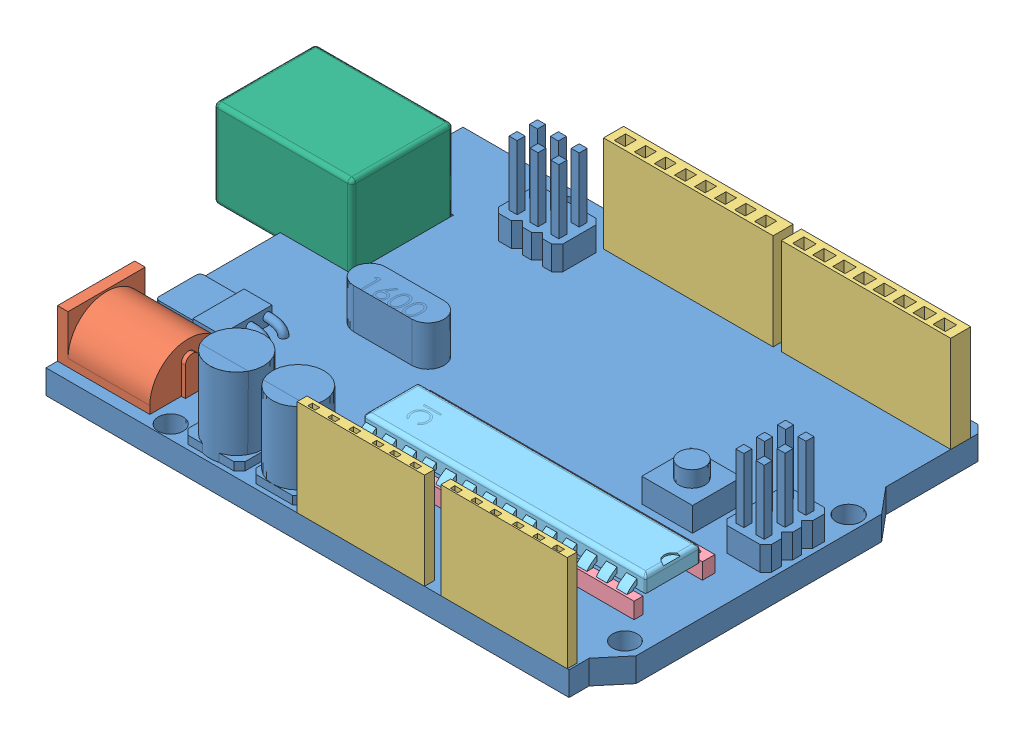
SolidWorks assembly Arduino Uno, configuration Predeterminado. Lengths in mm.
Overall size (76.16 15 51.98).
6 component instances, 6 part files, 11 mates.
Components (placement in the parent):
- Arduino Board-1: Arduino Board [Predeterminado] at (-14.2075 29.4682 76.4447) size (67.88 14 51.98)
- Jam Socket-1: Jam Socket [Predeterminado] at origin size (12.01 7 9.62)
- Pins Socket-1: Pins Socket [Predeterminado] at origin size (43.28 12 50.07)
- Socket IC-1: Socket IC [Predeterminado] at origin size (35.47 2 10.08)
- IC-1: IC [Predeterminado] at (0 34.4682 0) x (1 0 0) z (0 1 0) size (35.12 9.79 3)
- Port USB-1: Port USB [Predeterminado] at (-14.2075 31.4682 76.4447) x (1 0 0) z (0 1 0) size (17.2 12.69 11)
Mates (geometry in assembly coordinates):
- Coincidente1: coincident anti-aligned: plane of Arduino Board-1 through (-14.2075 32.4682 76.4447) normal (0 1 0); plane of Pins Socket-1 through (0 32.4682 0) normal (0 -1 0)
- Coincidente3: coincident aligned: plane of Arduino Board-1 through (51.0035 32.4682 75.4707) normal (0 0 1); plane of Pins Socket-1 through (0 44.4682 75.4707) normal (0 0 1)
- Coincidente4: coincident aligned: plane of Arduino Board-1 through (51.0035 32.4682 24.4939) normal (1 0 0); plane of Pins Socket-1 through (51.0035 44.4682 0) normal (1 0 0)
- EnPosición1: in place: plane of ? through (0 34.4682 0) normal (0 1 0); plane of IC-1 through (0 34.4682 0) normal (0 1 0); moOrthogonalPlaneRef_w of ? through (0 34.4682 0) normal (0 1 0); plane of IC-1 through (0 34.4682 0) normal (0 0 -1); plane of ? through (0 34.4682 0) normal (0 1 0); line of IC-1 through (-55 0 34.4682) axis (0 1 0); plane of ? through (0 34.4682 0) normal (0 1 0); unknown of IC-1
- Coincidente5: coincident aligned: plane of Socket IC-1; plane of IC-1
- Coincidente6: coincident aligned: moOrthogonalPlaneRef_w of Socket IC-1 through (0 34.4682 0) normal (0 0 -1); plane of IC-1 through (0 34.4682 0) normal (0 0 -1)
- Coincidente7: coincident anti-aligned: moOrthogonalPlaneRef_w of Socket IC-1 through (0 34.4682 0) normal (-1 0 0); plane of IC-1
- EnPosición2: in place: plane of Arduino Board-1 through (-14.2075 31.4682 76.4447) normal (0 1 0); plane of ? through (0 31.4682 0) normal (0 1 0); plane of Arduino Board-1 through (-14.2075 31.4682 76.4447) normal (0 1 0); plane of ? through (0 31.4682 0) normal (0 0 -1); plane of Arduino Board-1 through (-14.2075 31.4682 76.4447) normal (0 1 0); line of ? through (-55 0 31.4682) axis (0 1 0); plane of Arduino Board-1 through (-14.2075 31.4682 76.4447) normal (0 1 0); unknown of Port USB-1
- Coincidente8: coincident aligned: plane of Arduino Board-1; plane of Port USB-1
- Coincidente9: coincident aligned: moOrthogonalPlaneRef_w of Arduino Board-1 through (-14.2075 31.4682 76.4447) normal (0 0 -1); plane of Port USB-1 through (-14.2075 31.4682 76.4447) normal (0 0 -1)
- Coincidente10: coincident anti-aligned: moOrthogonalPlaneRef_w of Arduino Board-1 through (-14.2075 31.4682 76.4447) normal (-1 0 0); plane of Port USB-1
